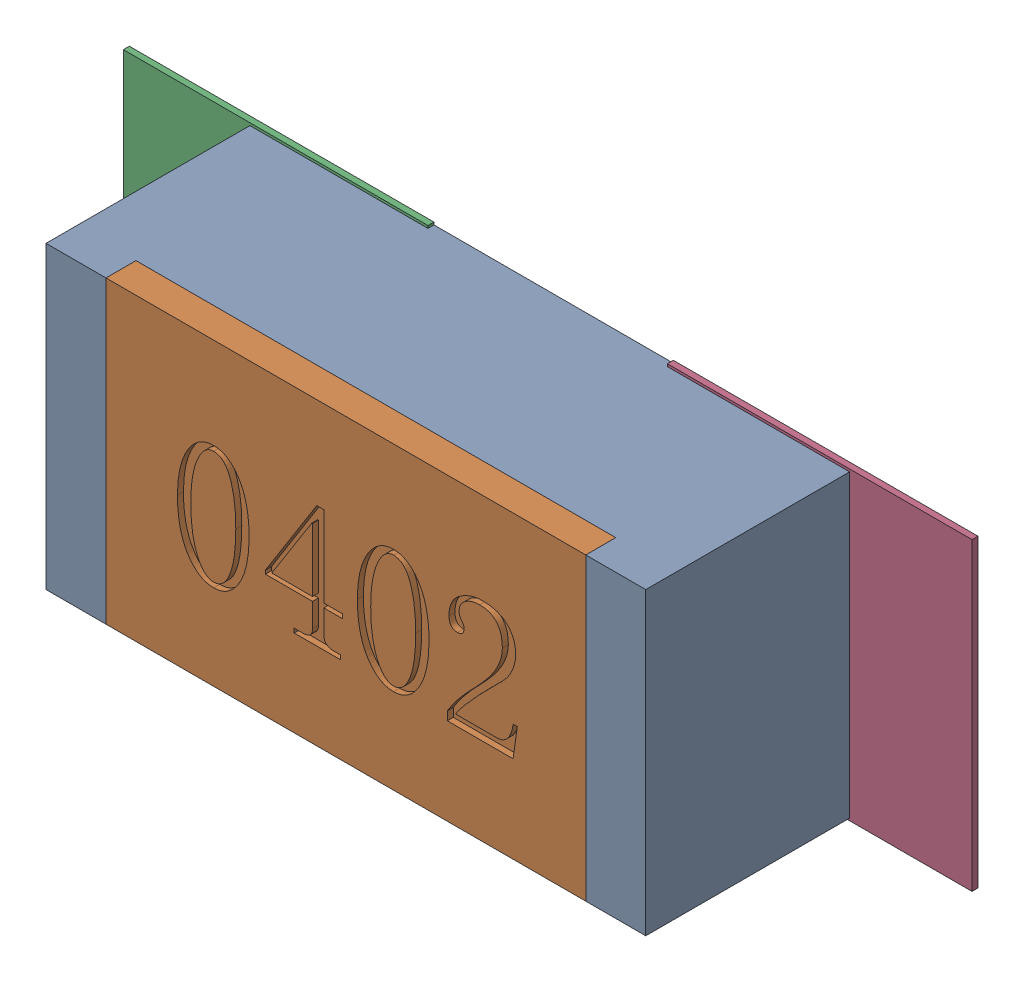
SolidWorks assembly R57, configuration Défaut. Lengths in mm.
Overall size (1.42 0.51 0.35).
5 component instances, 2 part files, 0 mates.
Components (placement in the parent):
- R0402-1: R0402 [Défaut] at (61.976 -19.0501 0) x (1 0 0) z (0 0 1) size (1 0.5 0.35)
- 6504207776-1: 6504207776 [Défaut] at (61.5189 -19.05 0) size (0.51 0.51 0.01)
  - Extruded-1: Extruded [Défaut] at origin size (0.51 0.51 0.01)
- 6504207776-2: 6504207776 [Défaut] at (62.426 -19.05 0) size (0.51 0.51 0.01)
  - Extruded-1: Extruded [Défaut] at origin size (0.51 0.51 0.01)
